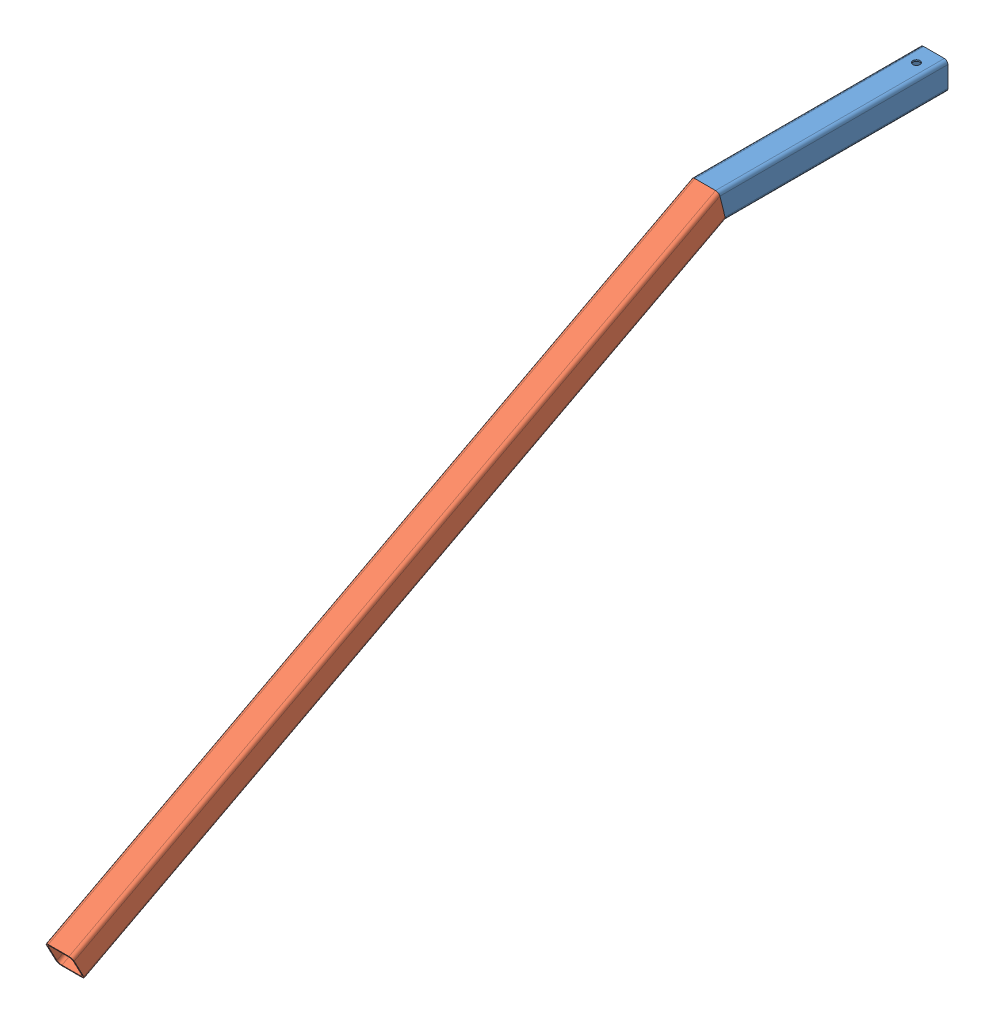
SolidWorks assembly ArmDeflection, configuration Default. Lengths in mm.
Overall size (20 263.02 631.58).
2 component instances, 2 part files, 2 mates.
Components (placement in the parent):
- Ballast_Arm_Link1-1: Ballast_Arm_Link1 [Default] at (58.1568 90.3682 43.1495) size (20 20 165.1)
- Ballast_Arm_Link2-1: Ballast_Arm_Link2 [Default] at (58.1568 -153.8032 670.0705) x (-1 0 0) z (0 0.46546 -0.885069) size (20 20 527.05)
Mates (geometry in assembly coordinates):
- Coincident1: coincident aligned: line of Ballast_Arm_Link1-1 through (48.1568 82.9082 203.9383) axis (0 0.970842 0.23972); line of Ballast_Arm_Link2-1 through (48.1568 82.9082 203.9383) axis (0 0.970842 0.23972)
- Coincident2: coincident anti-aligned: line of Ballast_Arm_Link1-1 through (65.6168 100.3682 208.2495) axis (-1 0 0); line of Ballast_Arm_Link2-1 through (50.6968 100.3682 208.2495) axis (1 0 0)
